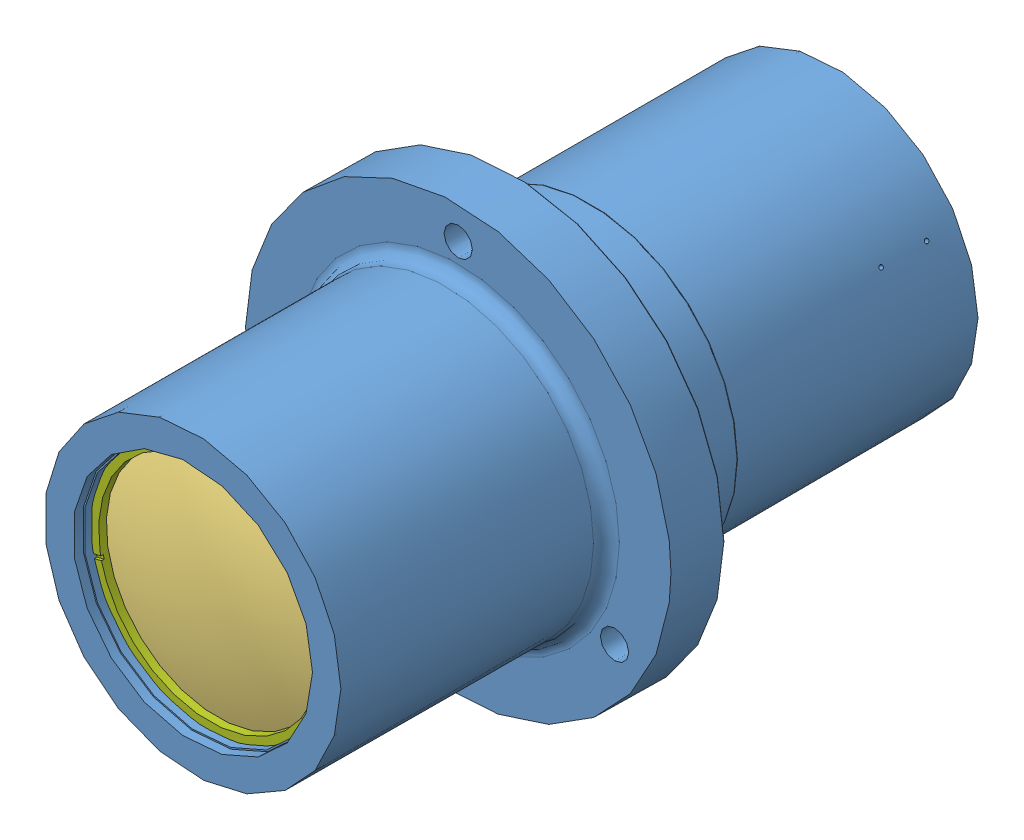
SolidWorks assembly holder_f, configuration Default. Lengths in mm.
Overall size (165 169.4 248.07).
14 component instances, 13 part files, 19 mates.
Components (placement in the parent):
- holder_f01-1: holder_f01 [Default] at origin size (165 169.4 248.07)
- G2-1: G2 [Default] at (-41.2621 501.0763 0.7815) x (0 0 -1) z (-0.996627 -0.082069 0) size (18.78 89 89)
- G1-1: G1 [Default] at (473.7345 176.7829 -115.8984) x (0 0 -1) z (-0.349619 0.936892 0) size (11.71 89 89)
- G3-1: G3 [Default] at (247.9633 -437.372 0.7856) x (0 0 -1) z (0.869921 0.493192 0) size (20.81 95 95)
- G4-1: G4 [Default] at (-370.3801 -339.998 98.9083) x (0 0 -1) z (0.676246 -0.736675 0) size (24 95 95)
- holder_f02-1: holder_f02 [ﾃﾞﾌｫﾙﾄ] at (0 0 226.8623) x (0.952021 0.306033 0) z (0 0 1) size (89 89 6.63)
- holder_f04-1: holder_f04 [ﾃﾞﾌｫﾙﾄ] at (0 0 238.548) x (-0.21425 0.976779 0) z (0 0 1) size (93 93.05 3.05)
- holder_f03-1: holder_f03 [ﾃﾞﾌｫﾙﾄ] at (0 0 15.0634) x (0.975523 -0.219897 0) z (0 0 1) size (95 95 5.55)
- holder_f05-1: holder_f05 [ﾃﾞﾌｫﾙﾄ] at (0 0 9.557) x (-0.949619 0.313407 0) z (0 0 -1) size (99 99.05 3.04)
- holder_f91-2: holder_f91 [Default] at (0 0 236.97) size (93 93 1.58)
- holder_f95-1: holder_f95 [Default] at (0 0 226.3313) size (99 99 1.54)
- holder_f93-2: holder_f93 [Default] at (0 0 37.23) size (95 95 0.26)
- holder_f94-2: holder_f94 [Default] at (0 0 14.2094) size (95 95 0.85)
- holder_f95-3: holder_f95 [Default] at (0 0 9.557) x (0.961987 -0.273095 0) z (0 0 1) size (99 99 1.54)
Mates (geometry in assembly coordinates):
- 一致1: coincident anti-aligned: plane of holder_f01-1 through (0 0 215.34) normal (0 0 1); plane of G2-1 through (3.6521 -44.3499 215.34) normal (0 0 -1)
- 一致2: coincident aligned: circle of holder_f01-1 centre (0 0 215.34) axis (0 0 1); circle of G2-1 centre (0 0 215.34) axis (0 0 1)
- 同心円1: concentric anti-aligned: cylinder of holder_f01-1; cylinder of holder_f02-1
- 同心円3: concentric anti-aligned: cylinder of G1-1; cylinder of holder_f02-1
- 同心円4: concentric anti-aligned: cylinder of holder_f01-1; cylinder of holder_f04-1
- 同心円7: concentric anti-aligned: cylinder of holder_f01-1; cylinder of G3-1
- 同心円8: concentric anti-aligned: cylinder of holder_f01-1; cylinder of G4-1
- 同心円9: concentric anti-aligned: cylinder of holder_f01-1; circle of holder_f03-1 centre (0 0 15.0634) axis (0 0 1)
- 同心円11: concentric anti-aligned: cylinder of holder_f05-1; cylinder of holder_f01-1
- 一致3: coincident anti-aligned: plane of G3-1 through (-23.4266 41.3212 20.6134) normal (0 0 -1); plane of holder_f03-1 through (0 0 20.6134) normal (0 0 1)
- 一致5: coincident anti-aligned: plane of holder_f01-1 through (0 0 236.97) normal (0 0 1); plane of holder_f91-2 through (0 0 236.97) normal (0 0 -1)
- 一致7: coincident anti-aligned: circle of G1-1 centre (0 0 233.4123) axis (0 0 -1); circle of holder_f02-1 centre (0 0 233.4123) axis (0 0 1)
- 一致10: coincident aligned: circle of G3-1 centre (0 0 37.23) axis (0 0 1); circle of holder_f93-2 centre (0 0 37.23) axis (0 0 1)
- 一致11: coincident aligned: circle of holder_f03-1 centre (0 0 15.0634) axis (0 0 1); circle of holder_f94-2 centre (0 0 15.0634) axis (0 0 1)
- 一致12: coincident aligned: circle of G4-1 centre (0 0 14.2094) axis (0 0 1); circle of holder_f94-2 centre (0 0 14.2094) axis (0 0 1)
- 同心円12: concentric anti-aligned: cylinder of holder_f05-1; cylinder of holder_f95-3
- 一致17: coincident anti-aligned: circle of holder_f05-1 centre (0 0 9.557) axis (0 0 -1); circle of holder_f95-3 centre (0 0 9.557) axis (0 0 1)
- 一致18: coincident anti-aligned: plane of holder_f01-1 through (0 0 11.1) normal (0 0 -1); plane of holder_f95-3 through (0 0 11.1) normal (0 0 1)
- 一致19: coincident anti-aligned: circle of holder_f93-2 centre (0 0 37.493) axis (0 0 1); circle of holder_f01-1 centre (0 0 37.493) axis (0 0 -1)
